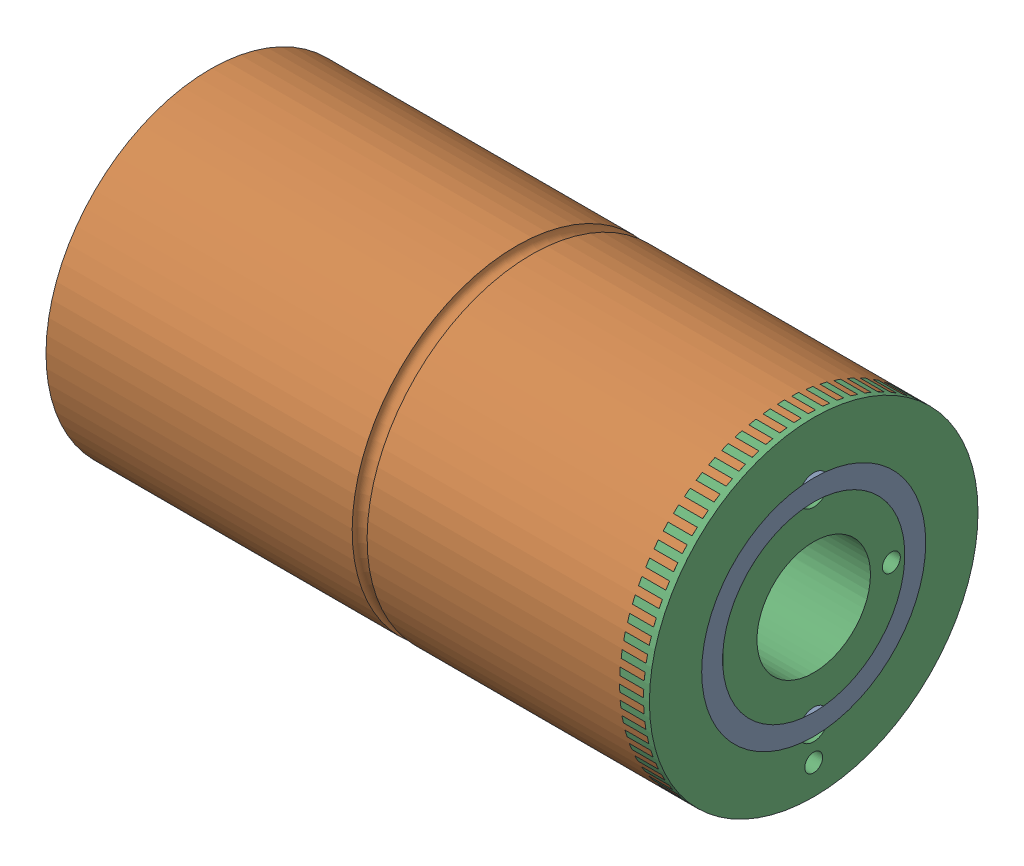
SolidWorks assembly Assem5, configuration Default. Lengths in mm.
Overall size (202 155.07 155.07).
3 component instances, 3 part files, 4 mates.
Components (placement in the parent):
- Part3.2-1: Part3.2 [Default] at (226.292 7.1097 -31.0972) x (0 0 -1) z (0 1 0) size (75 192 75)
- Part1.2-1: Part1.2 [Default] at (24.292 7.1097 -31.0972) x (1 0 0) z (0 -0.760905 0.648863) size (200 110 110)
- Part2.3-1: Part2.3 [Default] at (226.292 7.1097 -31.0972) x (-1 0 0) z (0 0 1) size (200 110 110)
Mates (geometry in assembly coordinates):
- Concentric1: concentric anti-aligned: circle of Part3.2-1; circle of Part1.2-1
- Coincident2: coincident anti-aligned: plane of Part3.2-1 through (34.292 7.1097 -31.0972) normal (-1 0 0); plane of Part1.2-1 through (34.292 7.1097 -31.0972) normal (1 0 0)
- Concentric2: concentric aligned: cylinder of Part1.2-1; cylinder of Part2.3-1 through (26.292 7.1097 -31.0972) axis (1 0 0) radius 22.5
- Coincident3: coincident anti-aligned: circle of Part1.2-1; plane of Part2.3-1 through (26.292 7.1097 -31.0972) normal (-1 0 0)
